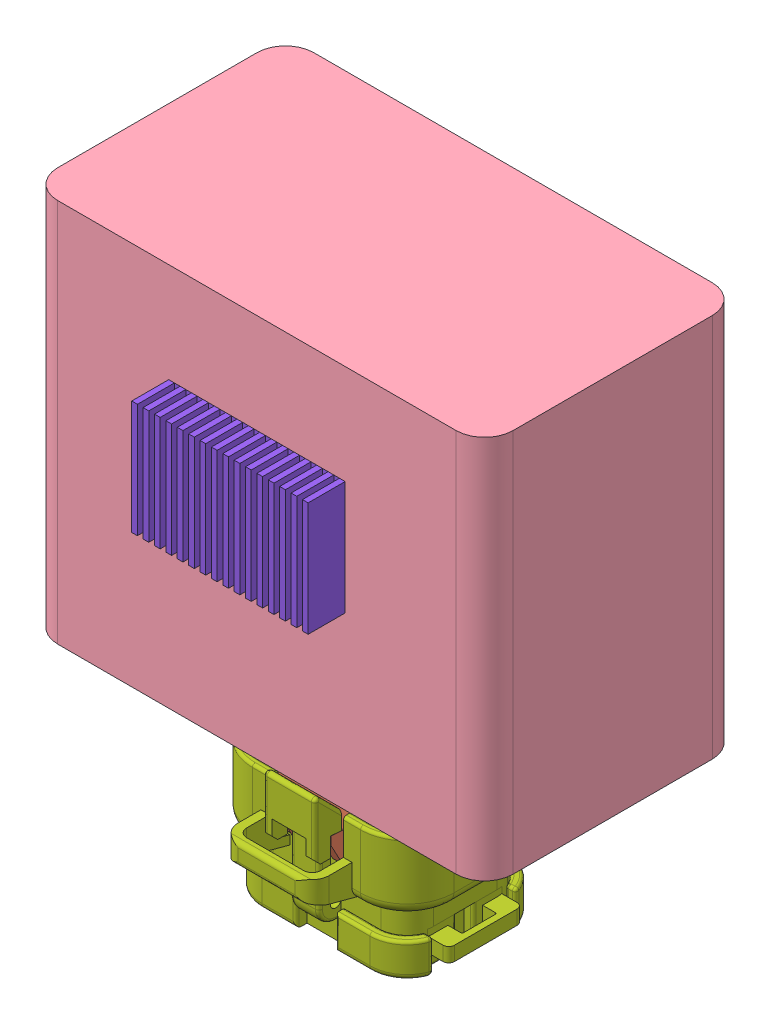
SolidWorks assembly PCB_TEST_ASSEM, configuration Default. Lengths in mm.
Overall size (80 100.56 51.5).
11 component instances, 8 part files, 30 mates.
Components (placement in the parent):
- ETBC_PCB_test-1: ETBC_PCB_test [Default] at origin size (56 56 1.5)
- AMP_14pin_panel_1-776267-1-1: AMP_14pin_panel_1-776267-1 [Default] at (0 -50 13.22) x (1 0 0) z (0 -1 0) size (49.81 32.1 37.8)
- PCB_FRONTPLATE_TEST-1: PCB_FRONTPLATE_TEST [Default] at (0 -30.75 13.22) x (1 0 0) z (0 -1 0) size (75 40 2)
- PCB_ENCLOSURE_TEST-1: PCB_ENCLOSURE_TEST [Default] at (0 -30.75 13.22) x (-1 0 0) z (0 1 0) size (80 45 67.5)
- PCB_FRAME_TEST-1: PCB_FRAME_TEST [Default] at (-1.3136 -26.7427 -0.0587) size (75 63 40)
- Threaded Insert-1: Threaded Insert [Default] at (-32.5016 -31.1635 28.22) x (-1 0 0) z (0 0 1) size (4 4.96 4)
- Threaded Insert-3: Threaded Insert [Default] at (-32.5016 -31.1635 -1.78) x (-1 0 0) z (0 0 1) size (4 4.96 4)
- Threaded Insert-5: Threaded Insert [Default] at (32.4984 -31.1635 28.22) x (-1 0 0) z (0 0 1) size (4 4.96 4)
- Threaded Insert-7: Threaded Insert [Default] at (32.4984 -31.1635 -1.78) x (-1 0 0) z (0 0 1) size (4 4.96 4)
- AMP_14pin_wire_776273-1-1: AMP_14pin_wire_776273-1 [Default] at (0 -40.6 13.22) x (-1 0 0) z (0 1 0) size (35.41 34.61 33.81)
- PCB_HEATSINK-1: PCB_HEATSINK [Default] at (-15.5 -0.75 27.22) size (31 20 15)
Mates (geometry in assembly coordinates):
- Coincident1: coincident anti-aligned: plane of AMP_14pin_panel_1-776267-1-1 through (0 -50 13.22) normal (-1 0 0); plane of assembly through (0 0 0) normal (1 0 0)
- Coincident2: coincident anti-aligned: plane of ETBC_PCB_TEST-1 through (0 0 1.5) normal (0 0 1); plane of AMP_14pin_panel_1-776267-1-1 through (11.745 -28 1.5) normal (0 0 -1)
- Coincident3: coincident anti-aligned: plane of ETBC_PCB_TEST-1 through (-28 -28 1.5) normal (0 -1 0); plane of AMP_14pin_panel_1-776267-1-1 through (0 -28 13.22) normal (0 1 0)
- InPlace1: in place: plane of AMP_14pin_panel_1-776267-1-1 through (0 -30.75 13.22) normal (0 -1 0); plane of ? through (0 -30.75 0) normal (0 -1 0); moOrthogonalPlaneRef_w of AMP_14pin_panel_1-776267-1-1 through (0 -30.75 13.22) normal (0 -1 0); plane of ? through (0 -30.75 0) normal (0 0 -1); plane of AMP_14pin_panel_1-776267-1-1 through (0 -30.75 13.22) normal (0 -1 0); plane of ? through (0 -30.75 0) normal (-1 0 0); plane of AMP_14pin_panel_1-776267-1-1 through (0 -30.75 13.22) normal (0 -1 0); unknown of PCB_FRONTPLATE_TEST-1
- Coincident4: coincident aligned: plane of AMP_14pin_panel_1-776267-1-1; plane of PCB_FRONTPLATE_TEST-1
- Coincident5: coincident aligned: moOrthogonalPlaneRef_w of AMP_14pin_panel_1-776267-1-1 through (0 -30.75 13.22) normal (0 0 1); plane of PCB_FRONTPLATE_TEST-1 through (0 -30.75 13.22) normal (0 0 1)
- Coincident6: coincident anti-aligned: moOrthogonalPlaneRef_w of AMP_14pin_panel_1-776267-1-1 through (0 -30.75 13.22) normal (-1 0 0); plane of PCB_FRONTPLATE_TEST-1 through (0 -30.75 13.22) normal (1 0 0)
- InPlace2: in place: plane of PCB_FRONTPLATE_TEST-1 through (32.5 -30.75 28.22) normal (0 1 0); plane of ? through (0 -30.75 0) normal (0 1 0); plane of PCB_FRONTPLATE_TEST-1 through (32.5 -30.75 28.22) normal (0 1 0); plane of ? through (0 -30.75 0) normal (0 0 -1); plane of PCB_FRONTPLATE_TEST-1 through (32.5 -30.75 28.22) normal (0 1 0); plane of ? through (0 -30.75 0) normal (1 0 0); plane of PCB_FRONTPLATE_TEST-1 through (32.5 -30.75 28.22) normal (0 1 0); unknown of PCB_ENCLOSURE_TEST-1
- Coincident7: coincident aligned: plane of PCB_FRONTPLATE_TEST-1; plane of PCB_ENCLOSURE_TEST-1
- Coincident8: coincident aligned: moOrthogonalPlaneRef_w of PCB_FRONTPLATE_TEST-1 through (0 -30.75 13.22) normal (0 0 1); plane of PCB_ENCLOSURE_TEST-1 through (0 -30.75 13.22) normal (0 0 1)
- Coincident9: coincident anti-aligned: moOrthogonalPlaneRef_w of PCB_FRONTPLATE_TEST-1 through (0 -30.75 13.22) normal (1 0 0); plane of PCB_ENCLOSURE_TEST-1 through (0 -30.75 13.22) normal (-1 0 0)
- Concentric1: concentric anti-aligned: cylinder of PCB_FRONTPLATE_TEST-1 through (-32.5 -32.75 28.22) axis (0 1 0) radius 1.5; cylinder of PCB_FRAME_TEST-1 through (-32.5 -20.75 28.22) axis (0 -1 0) radius 2
- Concentric2: concentric anti-aligned: cylinder of PCB_FRONTPLATE_TEST-1 through (32.5 -32.75 -1.78) axis (0 1 0) radius 1.5; cylinder of PCB_FRAME_TEST-1 through (32.5 -20.75 -1.78) axis (0 -1 0) radius 2
- Coincident4: coincident anti-aligned: plane of PCB_FRONTPLATE_TEST-1 through (32.5 -30.75 28.22) normal (0 1 0); plane of PCB_FRAME_TEST-1 through (-1.3136 -30.75 -0.0587) normal (0 -1 0)
- Concentric3: concentric aligned: cylinder of PCB_FRAME_TEST-1 through (-32.5 -20.75 28.22) axis (0 -1 0) radius 2; cylinder of Threaded Insert-1 through (-32.5 -30.75 28.22) axis (0 -1 0) radius 1.7834
- Coincident5: coincident aligned: plane of PCB_FRAME_TEST-1 through (-1.3136 -30.75 -0.0587) normal (0 -1 0); plane of Threaded Insert-1 through (-32.5 -30.75 28.22) normal (0 -1 0)
- Concentric4: concentric aligned: cylinder of PCB_FRAME_TEST-1 through (-32.5 -20.75 -1.78) axis (0 -1 0) radius 2; cylinder of Threaded Insert-3 through (-32.5 -30.75 -1.78) axis (0 -1 0) radius 1.7834
- Coincident6: coincident aligned: plane of PCB_FRAME_TEST-1 through (-1.3136 -30.75 -0.0587) normal (0 -1 0); plane of Threaded Insert-3 through (-32.5 -30.75 -1.78) normal (0 -1 0)
- Concentric5: concentric aligned: cylinder of PCB_FRAME_TEST-1 through (32.5 -20.75 28.22) axis (0 -1 0) radius 2; cylinder of Threaded Insert-5 through (32.5 -30.75 28.22) axis (0 -1 0) radius 1.7834
- Coincident7: coincident aligned: plane of PCB_FRAME_TEST-1 through (-1.3136 -30.75 -0.0587) normal (0 -1 0); plane of Threaded Insert-5 through (32.5 -30.75 28.22) normal (0 -1 0)
- Concentric6: concentric aligned: cylinder of PCB_FRAME_TEST-1 through (32.5 -20.75 -1.78) axis (0 -1 0) radius 2; cylinder of Threaded Insert-7 through (32.5 -30.75 -1.78) axis (0 -1 0) radius 1.7834
- Coincident8: coincident aligned: plane of PCB_FRAME_TEST-1 through (-1.3136 -30.75 -0.0587) normal (0 -1 0); plane of Threaded Insert-7 through (32.5 -30.75 -1.78) normal (0 -1 0)
- Coincident9: coincident aligned: plane of Threaded Insert-1 through (-32.5016 -31.1635 28.22) normal (-1 0 0); plane of Threaded Insert-3 through (-32.5016 -31.1635 -1.78) normal (-1 0 0)
- Coincident10: coincident aligned: plane of Threaded Insert-5 through (32.4984 -31.1635 28.22) normal (-1 0 0); plane of Threaded Insert-7 through (32.4984 -31.1635 -1.78) normal (-1 0 0)
- Coincident11: coincident anti-aligned: plane of AMP_14pin_panel_1-776267-1-1 through (0 -50 13.22) normal (1 0 0); plane of AMP_14pin_wire_776273-1-1 through (0 -40.6 13.22) normal (-1 0 0)
- Coincident12: coincident aligned: plane of AMP_14pin_panel_1-776267-1-1 through (0 -50 13.22) normal (0 0 1); plane of AMP_14pin_wire_776273-1-1 through (0 -40.6 13.22) normal (0 0 1)
- Distance2: distance = 9.4 mm anti-aligned: plane of AMP_14pin_wire_776273-1-1 through (0 -40.6 13.22) normal (0 1 0); plane of AMP_14pin_panel_1-776267-1-1 through (0 -50 13.22) normal (0 -1 0)
- Coincident13: coincident anti-aligned: plane of PCB_ENCLOSURE_TEST-1 through (15.5 -0.75 -9.281) normal (-1 0 0); plane of PCB_HEATSINK-1 through (15.5 19.25 27.22) normal (1 0 0)
- Coincident14: coincident anti-aligned: plane of PCB_ENCLOSURE_TEST-1 through (15.5 19.25 -9.281) normal (0 -1 0); plane of PCB_HEATSINK-1 through (-15.5 19.25 27.22) normal (0 1 0)
- Coincident15: coincident aligned: plane of PCB_ENCLOSURE_TEST-1 through (0 34.25 35.72) normal (0 0 1); plane of PCB_HEATSINK-1 through (-15.5 19.25 35.72) normal (0 0 1)
